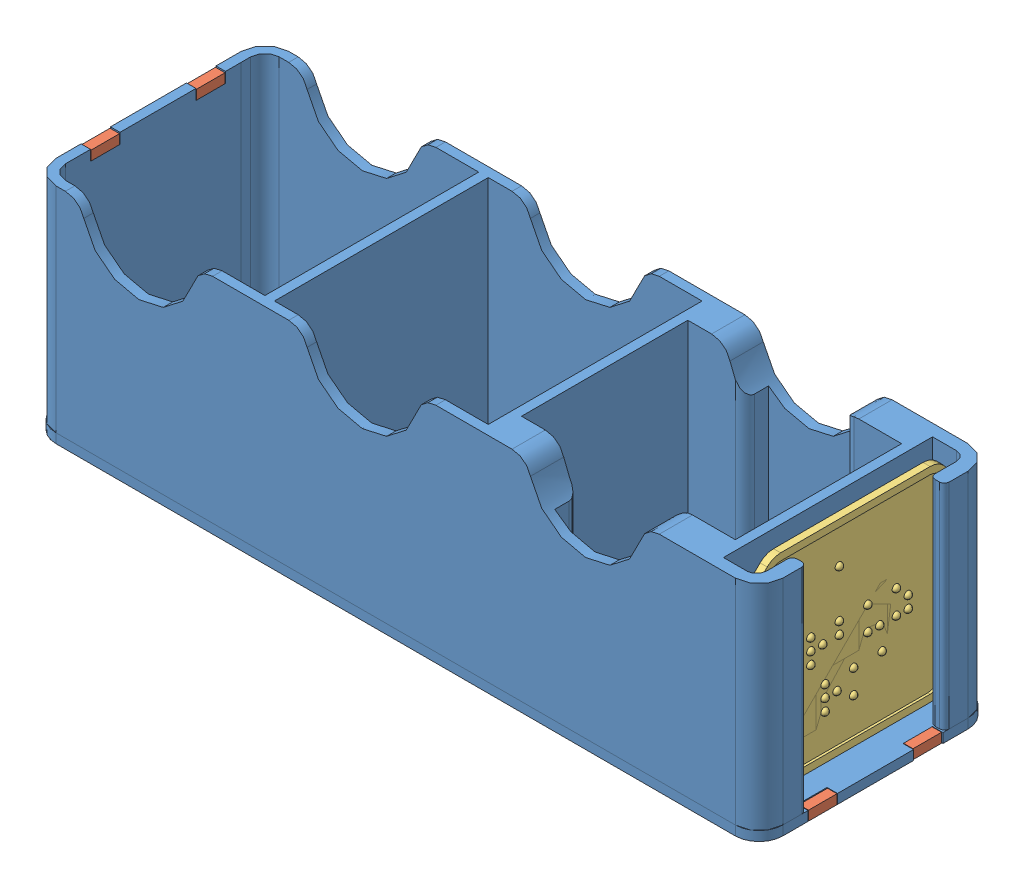
SolidWorks assembly box-assembly, configuration По умолчанию. Lengths in mm.
Overall size (153 47 49).
6 component instances, 3 part files, 16 mates.
Components (placement in the parent):
- box-1: box [По умолчанию] at origin size (153 47 49)
- magnet-prism-6x2x2-1: magnet-prism-6x2x2 [По умолчанию] at (-75.5 42.8 11.1) x (0 0 1) z (-1 0 0) size (6 2 2)
- magnet-prism-6x2x2-2: magnet-prism-6x2x2 [По умолчанию] at (-75.5 42.8 -11.1) x (0 0 1) z (-1 0 0) size (6 2 2)
- magnet-prism-6x2x2-10: magnet-prism-6x2x2 [По умолчанию] at (75.5 -2 11.1) x (0 0 -1) z (1 0 0) size (6 2 2)
- magnet-prism-6x2x2-12: magnet-prism-6x2x2 [По умолчанию] at (75.3 0 -11.1) x (0 0 -1) z (-1 0 0) size (6 2 2)
- а-арбуз-арка-1: а-арбуз-арка [По умолчанию] at (69 22.3399 0) x (0 0 -1) z (0 -1 0) size (43 1.75 43)
Mates (geometry in assembly coordinates):
- Совпадение1: coincident: plane of box-1 through (-76.5 45 0) normal (-1 0 0); plane of magnet-prism-6x2x2-1 through (-76.5 44.8 8.1) normal (-1 0 0)
- Совпадение2: coincident anti-aligned: plane of box-1 through (0 42.8 0) normal (0 1 0); plane of magnet-prism-6x2x2-1 through (-75.5 42.8 11.1) normal (0 -1 0)
- Расстояние1: distance = 0.1 mm: plane of magnet-prism-6x2x2-1 through (-74.5 44.8 8.1) normal (0 0 -1); plane of box-1 through (-76.5 42.8 8) normal (0 0 1)
- Совпадение4: coincident aligned: plane of box-1 through (-76.5 45 0) normal (-1 0 0); plane of magnet-prism-6x2x2-2 through (-76.5 44.8 -14.1) normal (-1 0 0)
- Совпадение5: coincident anti-aligned: plane of box-1 through (0 42.8 0) normal (0 1 0); plane of magnet-prism-6x2x2-2 through (-75.5 42.8 -11.1) normal (0 -1 0)
- Расстояние2: distance = 0.1 mm anti-aligned: plane of magnet-prism-6x2x2-2 through (-74.5 44.8 -14.1) normal (0 0 -1); plane of box-1 through (-76.5 42.8 -14.2) normal (0 0 1)
- Совпадение16: coincident aligned: plane of box-1 through (-76.5 45 0) normal (-1 0 0); plane of ? through (-76.5 44.8 10.8871) normal (-1 0 0)
- Совпадение17: coincident anti-aligned: plane of box-1 through (0 42.8 0) normal (0 1 0); plane of ? through (-75.5 42.8 13.8871) normal (0 -1 0)
- Совпадение19: coincident aligned: plane of box-1 through (0 -2 0) normal (0 -1 0); plane of magnet-prism-6x2x2-10 through (75.5 -2 11.1) normal (0 -1 0)
- Расстояние3: distance = 0.1 mm anti-aligned: plane of magnet-prism-6x2x2-10 through (74.5 0 14.1) normal (0 0 1); plane of box-1 through (74.3 0.2 14.2) normal (0 0 -1)
- Совпадение20: coincident aligned: plane of box-1 through (76.5 -2 0) normal (1 0 0); plane of magnet-prism-6x2x2-10 through (76.5 0 14.1) normal (1 0 0)
- Расстояние4: distance = 0.1 mm anti-aligned: plane of magnet-prism-6x2x2-12 through (76.3 -2 -8.1) normal (0 0 1); plane of box-1 through (74.3 0.2 -8) normal (0 0 -1)
- Совпадение23: coincident anti-aligned: plane of box-1 through (74.3 0.2 -8) normal (1 0 0); plane of magnet-prism-6x2x2-12 through (74.3 -2 -8.1) normal (-1 0 0)
- Совпадение24: coincident aligned: plane of box-1 through (0 0 0) normal (0 1 0); plane of magnet-prism-6x2x2-12 through (75.3 0 -11.1) normal (0 1 0)
- Расстояние5: distance = 0.5 mm anti-aligned: plane of а-арбуз-арка-1 through (70.5 36.3044 -21.5) normal (0 0 -1); plane of box-1 through (0 45 -22) normal (0 0 1)
- Расстояние6: distance = 2.5 mm anti-aligned: plane of а-арбуз-арка-1 through (69 36.3044 17.5) normal (-1 0 0); plane of box-1 through (66.5 45 0) normal (1 0 0)
